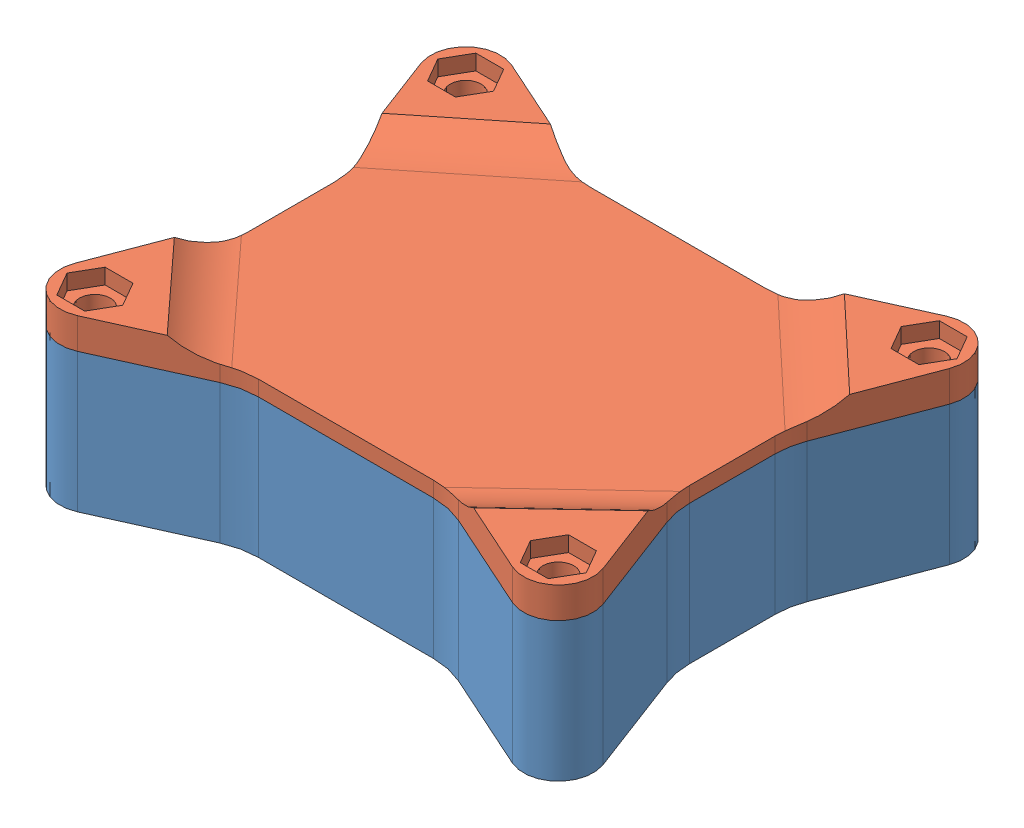
SolidWorks assembly Assem1, configuration Default. Lengths in mm.
Overall size (69 22 57).
2 component instances, 2 part files, 3 mates.
Components (placement in the parent):
- SensorHubTop-1: SensorHubTop [Default] at (-46.1002 -13.0231 27.0597) size (69 18 57)
- SensorHubPlate-1: SensorHubPlate [Default] at (-46.1002 4.9769 27.0597) size (69 4 57)
Mates (geometry in assembly coordinates):
- Coincident1: coincident: plane of SensorHubTop-1 through (-46.1002 4.9769 48.5597) normal (0 0 1); plane of SensorHubPlate-1 through (-46.1002 6.9769 48.5597) normal (0 0 1)
- Coincident2: coincident: plane of SensorHubTop-1 through (-17.6002 4.9769 27.0597) normal (1 0 0); plane of SensorHubPlate-1 through (-17.6002 6.9769 27.0597) normal (1 0 0)
- Coincident3: coincident anti-aligned: plane of SensorHubTop-1 through (-46.1002 4.9769 27.0597) normal (0 1 0); plane of SensorHubPlate-1 through (-46.1002 4.9769 27.0597) normal (0 -1 0)
